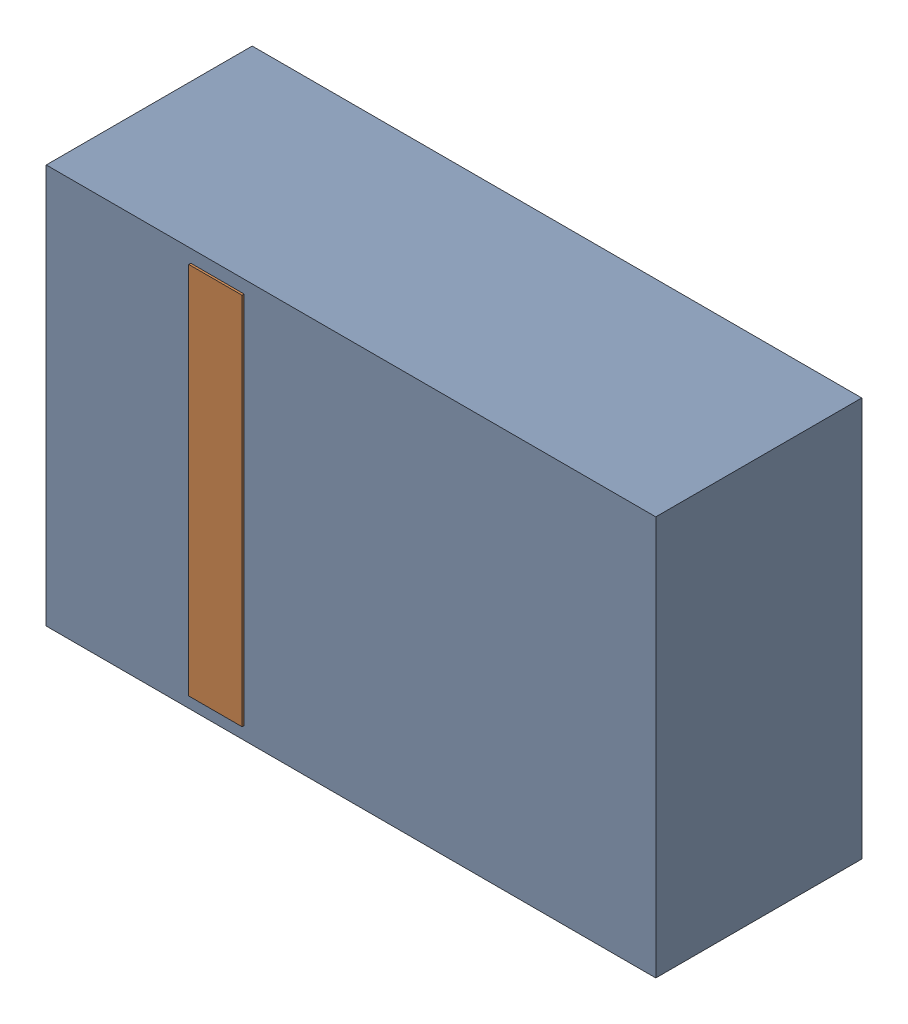
SolidWorks assembly D31, configuration Default. Lengths in mm.
Overall size (2.9 1.9 0.99).
4 component instances, 2 part files, 0 mates.
Components (placement in the parent):
- 905269392-1: 905269392 [Default] at (157.988 61.341 0) size (2.9 1.9 0.98)
  - Extruded_5-1: Extruded_5 [Default] at origin size (2.9 1.9 0.98)
- 905269800-1: 905269800 [Default] at (157.353 61.341 0.95) size (0.25 1.78 0.04)
  - Extruded_6-1: Extruded_6 [Default] at origin size (0.25 1.78 0.04)
